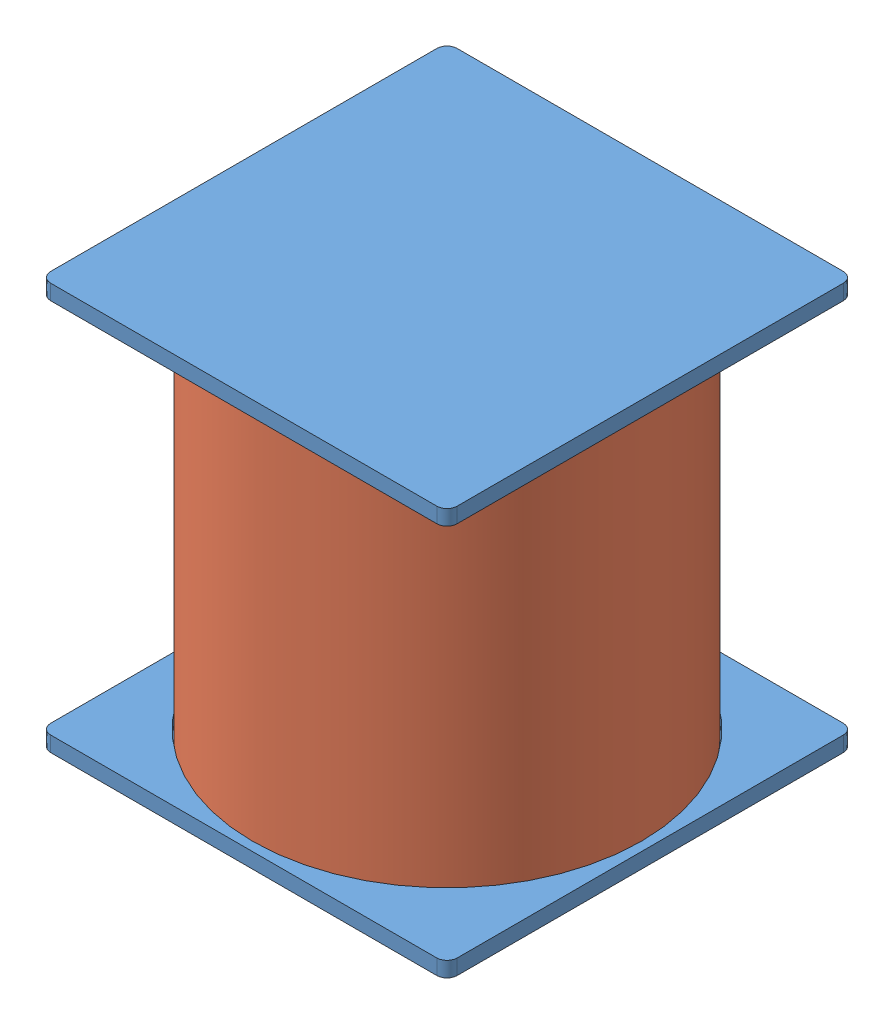
SolidWorks assembly Balises_passives_v3, configuration Default. Lengths in mm.
Overall size (98.49 80 98.49).
3 component instances, 2 part files, 5 mates.
Components (placement in the parent):
- support-1: support [Default] at (-25.4422 3.857 10.8051) size (80 3 80)
- support-2: support [Default] at (14.5578 83.857 -29.1949) x (0 0 1) z (1 0 0) size (80 3 80)
- cylindre_free-1: cylindre_free [Default] at (14.5578 4.857 10.8051) x (0.931081 0 0.364814) z (-0.364814 0 0.931081) size (76 78 76)
Mates (geometry in assembly coordinates):
- Coincident1: coincident anti-aligned: plane of support-1 through (14.5578 4.857 10.8051) normal (0 1 0); plane of cylindre_free-1 through (14.5578 4.857 10.8051) normal (0 -1 0)
- Concentric2: concentric aligned: circle of support-1; circle of cylindre_free-1
- Coincident4: coincident anti-aligned: plane of support-2 through (14.5578 82.857 10.8051) normal (0 -1 0); plane of cylindre_free-1 through (14.5578 82.857 10.8051) normal (0 1 0)
- Concentric3: concentric anti-aligned: circle of support-2; circle of cylindre_free-1
- Coincident5: coincident aligned: plane of support-1 through (-25.4422 6.857 50.8051) normal (0 0 1); plane of support-2 through (54.5578 80.857 50.8051) normal (0 0 1)
